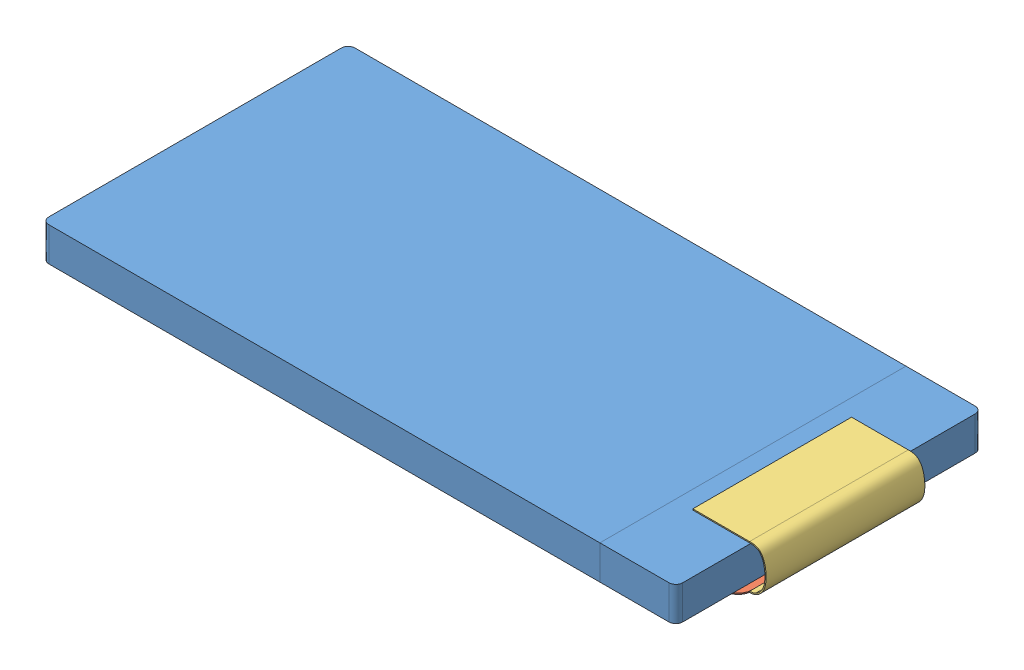
SolidWorks assembly 装配体1, configuration Default. Lengths in mm.
Overall size (28.69 1.96 13.5).
3 component instances, 3 part files, 8 mates.
Components (placement in the parent):
- 零件1-1: 零件1 [Default] at (16.0835 16.3581 15.2194) size (27.95 1.5 13.5)
- 零件2-1: 零件2 [Default] at (27.3613 16.0081 15.2194) size (10 0.05 12.4)
- 零件7^装配体1-1: 零件7^装配体1 [Default] at (30.0585 16.3581 15.2194) x (0 0 -1) z (1 0 0) size (8 1.96 3.24) (virtual)
Mates (geometry in assembly coordinates):
- 平行1: parallel aligned: line of 零件1-1 through (2.1085 16.3581 8.4694) axis (0 0 1); line of 零件2-1 through (20.0585 16.0581 19.6194) axis (0 0 1)
- 宽度1: width aligned: plane of 零件1-1 through (16.0835 17.8581 21.9694) normal (0 0 1); plane of 零件2-1 through (16.0835 17.8581 8.4694) normal (0 0 -1); plane of 零件1-1 through (27.3613 16.0581 21.4194) normal (0 0 1); plane of 零件2-1 through (27.3613 16.0581 9.0194) normal (0 0 -1)
- 距离1: distance = 0.3 mm anti-aligned: plane of 零件2-1 through (27.3613 16.0581 15.2194) normal (0 1 0); plane of 零件1-1 through (16.0835 16.3581 15.2194) normal (0 -1 0)
- 重合14: coincident aligned: plane of 零件1-1 through (30.0585 17.8581 15.2194) normal (1 0 0); plane of 零件2-1 through (30.0585 16.0581 15.2194) normal (1 0 0)
- 在位3: in place: plane of 零件1-1 through (30.0585 17.8581 15.2194) normal (1 0 0); plane of ? through (30.0585 0 0) normal (1 0 0); moOrthogonalPlaneRef_w of 零件1-1 through (30.0585 17.8581 15.2194) normal (1 0 0); plane of ? through (30.0585 0 0) normal (0 1 0); plane of 零件1-1 through (30.0585 17.8581 15.2194) normal (1 0 0); plane of ? through (30.0585 0 0) normal (0 0 -1); plane of 零件1-1 through (30.0585 17.8581 15.2194) normal (1 0 0); unknown of 零件7^装配体1-1
- 重合15: coincident aligned: plane of ?; plane of ?
- 重合16: coincident aligned: moOrthogonalPlaneRef_w of 零件1-1 through (30.0585 16.3581 15.2194) normal (0 1 0); plane of 零件7^装配体1-1 through (30.0585 16.3581 15.2194) normal (0 1 0)
- 重合17: coincident anti-aligned: moOrthogonalPlaneRef_w of 零件1-1 through (30.0585 16.3581 15.2194) normal (0 0 1); plane of 零件7^装配体1-1 through (30.0585 16.3581 15.2194) normal (0 0 -1)
